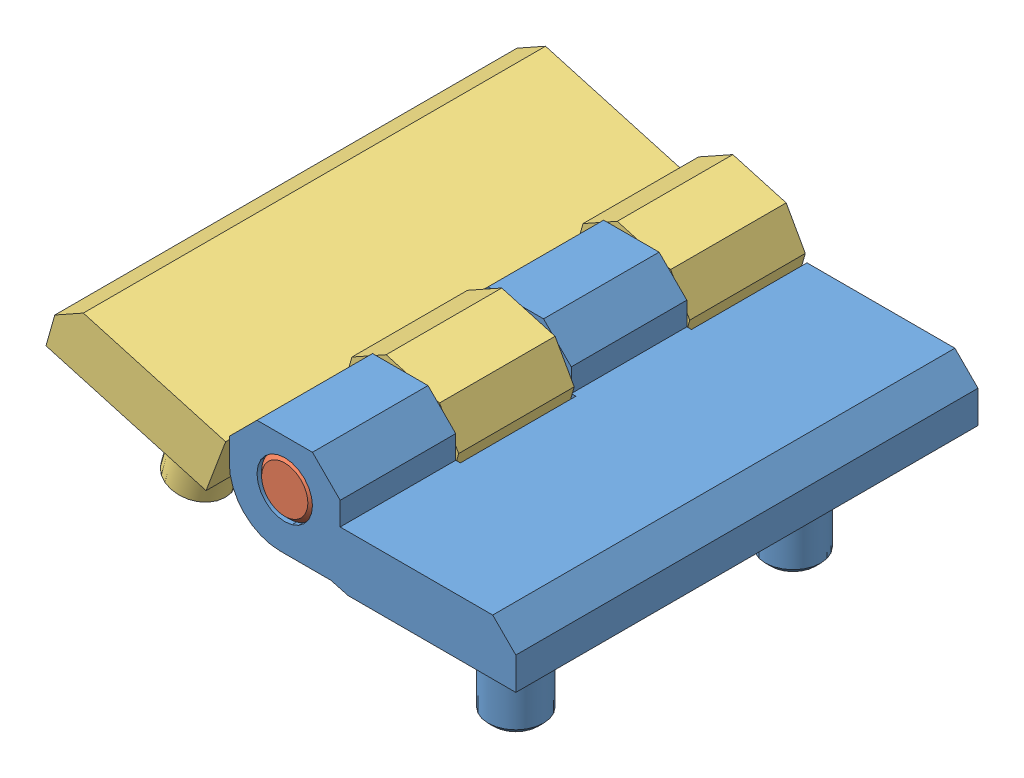
SolidWorks assembly Charniere EMKA 50 entraxe 30 M6 x12, configuration Défaut. Lengths in mm.
Overall size (54.09 31.06 50).
3 component instances, 3 part files, 5 mates.
Components (placement in the parent):
- Fixation gauche-1: Fixation gauche [Default] at (-57.4432 -2.2241 0) size (31 23.5 50)
- Axe-1: Axe [Default] at (-57.4432 -2.2241 0) size (6 6 50)
- Fixation droite-1: Fixation droite [Default] at (-59.2141 -1.9782 0) x (-0.962169 0.272452 0) z (0 0 -1) size (31 23.5 50)
Mates (geometry in assembly coordinates):
- Coaxiale1: concentric anti-aligned: cylinder of Fixation gauche-1 through (-57.4432 4.2759 25) axis (0 0 -1) radius 3; cylinder of Axe-1 through (-57.4432 4.2759 -25) axis (0 0 1) radius 3
- Coïncidente1: coincident aligned: plane of Fixation gauche-1 through (-57.4432 -2.2241 25) normal (0 0 1); plane of Axe-1 through (-57.4432 4.2759 25) normal (0 0 1)
- Coïncidente2: coincident aligned: plane of Axe-1 through (-57.4432 4.2759 -25) normal (0 0 -1); plane of Fixation droite-1 through (-59.2141 -1.9782 -25) normal (0 0 -1)
- Coaxiale2: concentric aligned: cylinder of Axe-1 through (-57.4432 4.2759 -25) axis (0 0 1) radius 3; cylinder of Fixation droite-1 through (-57.4432 4.2759 -25) axis (0 0 1) radius 3
- AngleLimite1: limit planar angle = 2.865652 rad anti-aligned: plane of Fixation droite-1 through (-53.4411 -3.6129 12.5) normal (-0.272452 -0.962169 0); plane of Fixation gauche-1 through (-63.4432 -2.2241 -12.5) normal (0 -1 0)
